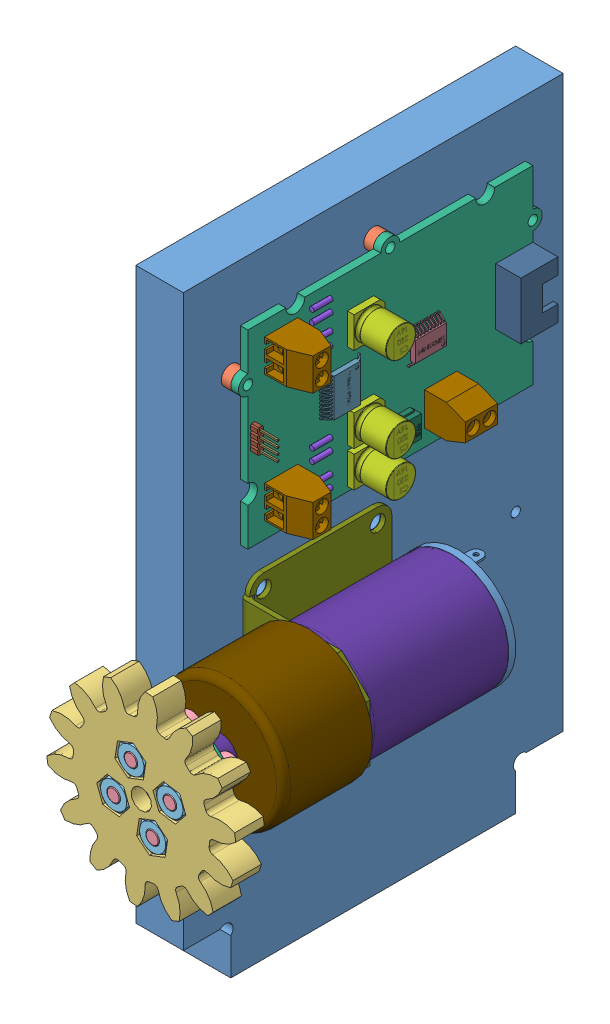
SolidWorks assembly moteur-complet, configuration Défaut. Lengths in mm.
Overall size (63.55 130 103.25).
60 component instances, 25 part files, 28 mates.
Components (placement in the parent):
- moteur-platine-1: moteur-platine [Défaut] at (-59.9962 -68.9698 170) size (10 130 80)
- Grove button-1: Grove button [Défaut] at (-60.7015 -11.8903 110) x (0 -1 0) z (0 0 -1) size (20 11.6 23.6)
  - PCB grove 20x20-1: PCB grove 20x20 [Défaut] at (2.0795 1.2947 0) size (20 1.6 23.6)
  - 603 resistor 102-1: 603 resistor 102 [Default] at (2.0895 2.8947 -6.319) x (0 0 1) z (-1 0 0) size (2.36 0.62 1.03)
  - tactileswitch-CMS-1: tactileswitch-CMS [Default] at (-2.4169 2.8947 0.0035) x (0 0 1) z (-1 0 0) size (8.41 4.95 6.01)
  - Connecteur Grove (droit CMS)-1: Connecteur Grove (droit CMS) [Défaut] at (5.0795 2.8947 0) x (-1 0 0) z (0 1 0) size (6.5 14 10)
  - 603 resistor 102-2: 603 resistor 102 [Default] at (3.5895 2.8947 -6.319) x (0 0 1) z (-1 0 0) size (2.36 0.62 1.03)
- Grove I2C Motor driver TB6612FNG-1: Grove I2C Motor driver TB6612FNG [Défaut] at (-111.1962 28.5169 135.6463) x (0 0 1) z (1 0 0) size (64 44 12.2)
  - Plaque de base-1: Plaque de base [Défaut] at (-5.6463 -2.5133 63.2) size (64 44 1.6)
  - CS 220 16V-1: CS 220 16V [Défaut] at (0.1237 13.2167 64.8) x (1 0 0) z (0 -1 0) size (6.54 8.01 6.54)
  - CS 220 16V-2: CS 220 16V [Défaut] at (0.1237 5.6767 64.8) x (1 0 0) z (0 -1 0) size (6.54 8.01 6.54)
  - CS 220 16V-3: CS 220 16V [Défaut] at (0.1237 -12.2433 64.8) x (1 0 0) z (0 -1 0) size (6.54 8.01 6.54)
  - D1-1: D1 [Défaut] at (7.4081 5.2819 65.3) x (0 0.946795 -0.321836) z (1 0 0) size (1 1 4)
  - D1-2: D1 [Défaut] at (7.4081 7.7235 65.3) x (0 0.786026 0.618193) z (1 0 0) size (1 1 4)
  - D1-3: D1 [Défaut] at (7.4081 14.4025 65.3) x (0 0.953842 0.300308) z (1 0 0) size (1 1 4)
  - D1-4: D1 [Défaut] at (7.4081 11.9602 65.3) x (0 0.659384 0.751806) z (1 0 0) size (1 1 4)
  - D1-5: D1 [Défaut] at (7.4081 -17.5815 65.3) x (0 -0.999835 -0.018161) z (1 0 0) size (1 1 4)
  - D1-6: D1 [Défaut] at (7.4081 -14.133 65.3) x (0 0.806812 -0.590809) z (1 0 0) size (1 1 4)
  - D1-7: D1 [Défaut] at (7.4081 -11.4343 65.3) x (0 -0.166774 0.985995) z (1 0 0) size (1 1 4)
  - D1-8: D1 [Défaut] at (7.4081 -20.0356 65.3) x (0 0.962631 -0.270816) z (1 0 0) size (1 1 4)
  - bornier double-1: bornier double [Défaut] at (20.8537 7.1995 64.8) x (0 1 0) z (1 0 0) size (6.8 12.2 7)
  - bornier double-2: bornier double [Défaut] at (-12.8463 13.9867 64.8) x (-1 0 0) z (0 1 0) size (6.8 12.2 7)
  - bornier double-3: bornier double [Défaut] at (20.8537 -19.5133 64.8) x (0 1 0) z (1 0 0) size (6.8 12.2 7)
  - Grove Connecteur-1: Grove Connecteur [Défaut] at (-37.0963 -2.5133 64.05) x (1 0 0) z (0 -1 0) size (7.8 5.3 12)
  - Bloc 4 pins male-1: Bloc 4 pins male [Défaut] at (23.2493 -0.7812 63.276) x (0 -1 0) z (0 0 1) size (5.08 1.27 7.62)
    - Pin_cmi2c_Base-1: Pin_cmi2c_Base [Défaut] at (-0.1729 -0.0306 1.524) size (1.27 1.27 1.52)
    - Pin_cmi2c-1: Pin_cmi2c [Défaut] at (-0.1729 0.1472 -0.762) x (1 0 0) z (0 -1 0) size (0.36 7.62 0.36)
    - Pin_cmi2c-2: Pin_cmi2c [Défaut] at (1.0971 0.1472 -0.762) x (1 0 0) z (0 -1 0) size (0.36 7.62 0.36)
    - Pin_cmi2c-3: Pin_cmi2c [Défaut] at (2.3671 0.1472 -0.762) x (1 0 0) z (0 -1 0) size (0.36 7.62 0.36)
    - Pin_cmi2c-4: Pin_cmi2c [Défaut] at (3.6371 0.1472 -0.762) x (1 0 0) z (0 -1 0) size (0.36 7.62 0.36)
    - Pin_cmi2c_Base-2: Pin_cmi2c_Base [Défaut] at (1.0971 -0.0306 1.524) size (1.27 1.27 1.52)
    - Pin_cmi2c_Base-3: Pin_cmi2c_Base [Défaut] at (2.3671 -0.0306 1.524) size (1.27 1.27 1.52)
    - Pin_cmi2c_Base-4: Pin_cmi2c_Base [Défaut] at (3.6371 -0.0306 1.524) size (1.27 1.27 1.52)
  - Microcontroller 32F030F4P6-1: Microcontroller 32F030F4P6 [Défaut] at (-12.4961 -2.5519 65.5199) size (6.61 6.93 1.72)
  - Microcontroller TB6612FNG-1: Microcontroller TB6612FNG [Défaut] at (5.1421 -2.7086 65.5199) x (0 1 0) z (0 0 1) size (8 8.26 1.72)
  - PK13-1: PK13 [Défaut] at (-8.5328 11.2953 64.8) x (0 -1 0) z (-1 0 0) size (5.33 2 3.32)
- moteur MFA-1: moteur MFA [Défaut] at (-37.4916 -12.5198 142.6632) x (0 0 -1) z (0 -1 0) size (69.13 27.9 30)
  - moteur-support-1: moteur-support [Défaut] at (-14.3868 -12.5047 0) size (31 26.4 30)
  - moteur-corps-1: moteur-corps [Défaut] at (14.8132 1.8953 0) x (0 0 1) z (-1 0 0) size (24 24 62.63)
  - moteur-capuchon-1: moteur-capuchon [Défaut] at (-15.3868 1.8953 0) x (0 0 1) z (-1 0 0) size (27 27 18.7)
  - moteur-arriere-1: moteur-arriere [Défaut] at (16.3132 1.8953 0) x (0 0 1) z (-1 0 0) size (24 24 6.5)
- entretoise-grove-1: entretoise-grove [Défaut] at (-47.9962 51.0302 130) x (0 0.271539 0.962428) z (-1 0 0) size (4 4 2)
- entretoise-grove-2: entretoise-grove [Défaut] at (-47.9962 41.0302 100) x (0 0.358036 0.933708) z (-1 0 0) size (4 4 2)
- entretoise-grove-3: entretoise-grove [Défaut] at (-47.9962 41.0302 160) x (0 -0.42455 0.905404) z (-1 0 0) size (4 4 2)
- entretoise-grove-4: entretoise-grove [Défaut] at (-47.9962 11.0302 150) x (0 0 1) z (-1 0 0) size (4 4 2)
- entretoise-grove-5: entretoise-grove [Défaut] at (-47.9962 11.0302 110) x (0 0.014886 0.999889) z (-1 0 0) size (4 4 2)
- entretoise-grove-6: entretoise-grove [Défaut] at (-61.9962 -13.9698 120) x (0 0 -1) z (1 0 0) size (4 4 2)
- entretoise-grove-7: entretoise-grove [Défaut] at (-61.9962 -13.9698 100) x (0 0 -1) z (1 0 0) size (4 4 2)
- engrenage-complet-1: engrenage-complet [Défaut] at (-35.1676 -12.7474 193.25) x (0.932852 0.36026 0) z (0 0 -1) size (39.32 40 13)
  - engrenage-1: engrenage [Défaut] at (1.0609 0.1936 0) size (39.32 40 6)
  - vis-chc-2: vis-chc [Vis CHC M3x10] at (6.0322 -0.3667 10) x (0.997256 0.074024 0) z (0.074024 -0.997256 0) size (5.5 13 5.5)
  - ecrou-h-1: ecrou-h [6012 HU M3] at (6.0322 -0.3667 0.1) x (1 0 0) z (0 1 0) size (5.5 2.4 6.35)
  - engrenage-moyeu-1: engrenage-moyeu [Défaut] at (-0.3178 -0.3667 7.5) x (0.707107 -0.707107 0) z (0 0 1) size (19 19 5)
  - vis-chc-3: vis-chc [Vis CHC M3x10] at (-0.3178 5.9833 10) x (0.997256 0.074024 0) z (0.074024 -0.997256 0) size (5.5 13 5.5)
  - vis-chc-4: vis-chc [Vis CHC M3x10] at (-6.6678 -0.3667 10) x (0.997256 0.074024 0) z (0.074024 -0.997256 0) size (5.5 13 5.5)
  - vis-chc-5: vis-chc [Vis CHC M3x10] at (-0.3178 -6.7167 10) x (0.997256 0.074024 0) z (0.074024 -0.997256 0) size (5.5 13 5.5)
  - ecrou-h-2: ecrou-h [6012 HU M3] at (-6.6678 -0.3667 0.1) x (0.5 0.866025 0) z (-0.866025 0.5 0) size (5.5 2.4 6.35)
  - ecrou-h-3: ecrou-h [6012 HU M3] at (-0.3178 5.9833 0.1) x (0.866025 0.5 0) z (-0.5 0.866025 0) size (5.5 2.4 6.35)
  - ecrou-h-4: ecrou-h [6012 HU M3] at (-0.3178 -6.7167 0.1) x (0.866025 0.5 0) z (-0.5 0.866025 0) size (5.5 2.4 6.35)
- vis-sthc-m3x5-1: vis-sthc-m3x5 [Défaut] at (-38.4304 -18.9204 185.75) x (0.517554 -0.229174 -0.824389) z (-0.404884 -0.914368 0) size (3.08 3.15 5.22)
Mates (geometry in assembly coordinates):
- Coïncidente1: coincident anti-aligned: plane of moteur-platine-1 through (-49.9962 -60.1012 161.1314) normal (1 0 0); plane of moteur MFA 12-24V-1/Support moteur-1 through (-49.9962 -24.5198 154.05) normal (-1 0 0)
- Coaxiale1: concentric anti-aligned: cylinder of moteur-platine-1 through (-59.9962 -0.5198 130.05) axis (1 0 0) radius 1.5; cylinder of moteur MFA 12-24V-1/Support moteur-1 through (-23.5962 -0.5198 130.05) axis (-1 0 0) radius 1.65
- Coaxiale2: concentric anti-aligned: cylinder of moteur-platine-1 through (-59.9962 -24.5198 130.05) axis (1 0 0) radius 1.5; cylinder of moteur MFA 12-24V-1/Support moteur-1 through (-23.5962 -24.5198 130.05) axis (-1 0 0) radius 1.65
- Parallèle1: parallel aligned: plane of moteur-platine-1 through (-49.9962 61.0302 90) normal (0 0 -1); plane of Grove I2C Motor driver TB6612FNG-1/Plaque de base-1 through (-46.3962 11.0302 100) normal (0 0 -1)
- Parallèle2: parallel aligned: plane of moteur-platine-1 through (-49.9962 61.0302 170) normal (0 1 0); plane of Grove I2C Motor driver TB6612FNG-1/Plaque de base-1 through (-46.3962 51.0302 132) normal (0 1 0)
- Coaxiale3: concentric anti-aligned: cylinder of Grove I2C Motor driver TB6612FNG-1/Plaque de base-1 through (-46.3962 11.0302 110) axis (-1 0 0) radius 1; cylinder of entretoise-grove-5 through (-49.9962 11.0302 110) axis (1 0 0) radius 1.2
- Coïncidente4: coincident anti-aligned: plane of Grove I2C Motor driver TB6612FNG-1/Plaque de base-1 through (-47.9962 21.0302 100) normal (-1 0 0); plane of entretoise-grove-5 through (-47.9962 11.0302 110) normal (1 0 0)
- Coaxiale4: concentric anti-aligned: cylinder of Grove I2C Motor driver TB6612FNG-1/Plaque de base-1 through (-46.3962 11.0302 150) axis (-1 0 0) radius 1; cylinder of entretoise-grove-4 through (-49.9962 11.0302 150) axis (1 0 0) radius 1.2
- Coïncidente5: coincident anti-aligned: plane of Grove I2C Motor driver TB6612FNG-1/Plaque de base-1 through (-47.9962 21.0302 100) normal (-1 0 0); plane of entretoise-grove-4 through (-47.9962 11.0302 150) normal (1 0 0)
- Coaxiale5: concentric anti-aligned: cylinder of Grove I2C Motor driver TB6612FNG-1/Plaque de base-1 through (-46.3962 41.0302 100) axis (-1 0 0) radius 1; cylinder of entretoise-grove-2 through (-49.9962 41.0302 100) axis (1 0 0) radius 1.2
- Coïncidente6: coincident anti-aligned: plane of Grove I2C Motor driver TB6612FNG-1/Plaque de base-1 through (-47.9962 21.0302 100) normal (-1 0 0); plane of entretoise-grove-2 through (-47.9962 41.0302 100) normal (1 0 0)
- Coaxiale6: concentric anti-aligned: cylinder of Grove I2C Motor driver TB6612FNG-1/Plaque de base-1 through (-46.3962 41.0302 160) axis (-1 0 0) radius 1; cylinder of entretoise-grove-3 through (-49.9962 41.0302 160) axis (1 0 0) radius 1.2
- Coïncidente7: coincident anti-aligned: plane of Grove I2C Motor driver TB6612FNG-1/Plaque de base-1 through (-47.9962 21.0302 100) normal (-1 0 0); plane of entretoise-grove-3 through (-47.9962 41.0302 160) normal (1 0 0)
- Coaxiale7: concentric anti-aligned: cylinder of Grove I2C Motor driver TB6612FNG-1/Plaque de base-1 through (-46.3962 51.0302 130) axis (-1 0 0) radius 1; cylinder of entretoise-grove-1 through (-49.9962 51.0302 130) axis (1 0 0) radius 1.2
- Coïncidente8: coincident anti-aligned: plane of Grove I2C Motor driver TB6612FNG-1/Plaque de base-1 through (-47.9962 21.0302 100) normal (-1 0 0); plane of entretoise-grove-1 through (-47.9962 51.0302 130) normal (1 0 0)
- Coïncidente9: coincident anti-aligned: plane of moteur-platine-1 through (-49.9962 -60.1012 161.1314) normal (1 0 0); plane of entretoise-grove-3 through (-49.9962 41.0302 160) normal (-1 0 0)
- Coaxiale8: concentric aligned: cylinder of moteur-platine-1 through (-59.9962 11.0302 150) axis (1 0 0) radius 1; cylinder of entretoise-grove-4 through (-49.9962 11.0302 150) axis (1 0 0) radius 1.2
- Coaxiale9: concentric anti-aligned: cylinder of Grove button-1/PCB grove 20x20-1 through (-63.5962 -13.9698 120) axis (1 0 0) radius 1.1; cylinder of entretoise-grove-6 through (-59.9962 -13.9698 120) axis (-1 0 0) radius 1.2
- Coaxiale10: concentric anti-aligned: cylinder of Grove button-1/PCB grove 20x20-1 through (-63.5962 -13.9698 100) axis (1 0 0) radius 1.1; cylinder of entretoise-grove-7 through (-59.9962 -13.9698 100) axis (-1 0 0) radius 1.2
- Coïncidente11: coincident anti-aligned: plane of Grove button-1/PCB grove 20x20-1 through (-61.9962 -13.9698 110) normal (1 0 0); plane of entretoise-grove-7 through (-61.9962 -13.9698 100) normal (-1 0 0)
- Coïncidente12: coincident anti-aligned: plane of Grove button-1/PCB grove 20x20-1 through (-61.9962 -13.9698 110) normal (1 0 0); plane of entretoise-grove-6 through (-61.9962 -13.9698 120) normal (-1 0 0)
- Coïncidente13: coincident anti-aligned: plane of moteur-platine-1 through (-59.9962 -60.1012 161.1314) normal (-1 0 0); plane of entretoise-grove-7 through (-59.9962 -13.9698 100) normal (1 0 0)
- Coaxiale11: concentric anti-aligned: cylinder of moteur-platine-1 through (-59.9962 -13.9698 100) axis (1 0 0) radius 1; cylinder of entretoise-grove-7 through (-59.9962 -13.9698 100) axis (-1 0 0) radius 1.2
- Coaxiale12: concentric anti-aligned: cylinder of moteur-platine-1 through (-59.9962 -13.9698 120) axis (1 0 0) radius 1; cylinder of entretoise-grove-6 through (-59.9962 -13.9698 120) axis (-1 0 0) radius 1.2
- Distance2: distance = 10.5 mm anti-aligned: plane of engrenage-complet-1/engrenage-1 through (-35.5962 -12.5198 187.25) normal (0 0 -1); plane of moteur MFA-1/moteur-capuchon-1 through (-35.5962 -12.5198 176.75) normal (0 0 1)
- Coaxiale13: concentric aligned: cylinder of engrenage-complet-1/engrenage-moyeu-1 through (-42.0744 -27.1497 185.75) axis (0.404884 0.914368 0) radius 1.5; cone of vis-sthc-m3x5-1 through (-36.5072 -14.5771 185.75) axis (0.404884 0.914368 0)
- Coaxiale14: concentric anti-aligned: cylinder of moteur MFA-1/moteur-corps-1 through (-35.5962 -12.5198 190.48) axis (0 0 -1) radius 2; cylinder of engrenage-complet-1/engrenage-moyeu-1 through (-35.5962 -12.5198 183.25) axis (0 0 1) radius 2
- Tangent1: tangent anti-aligned: cylinder of moteur MFA-1/moteur-corps-1 through (-35.5962 -12.5198 190.48) axis (0 0 -1) radius 2; plane of vis-sthc-m3x5-1 through (-36.406 -14.3485 185.75) normal (0.404884 0.914368 0)
